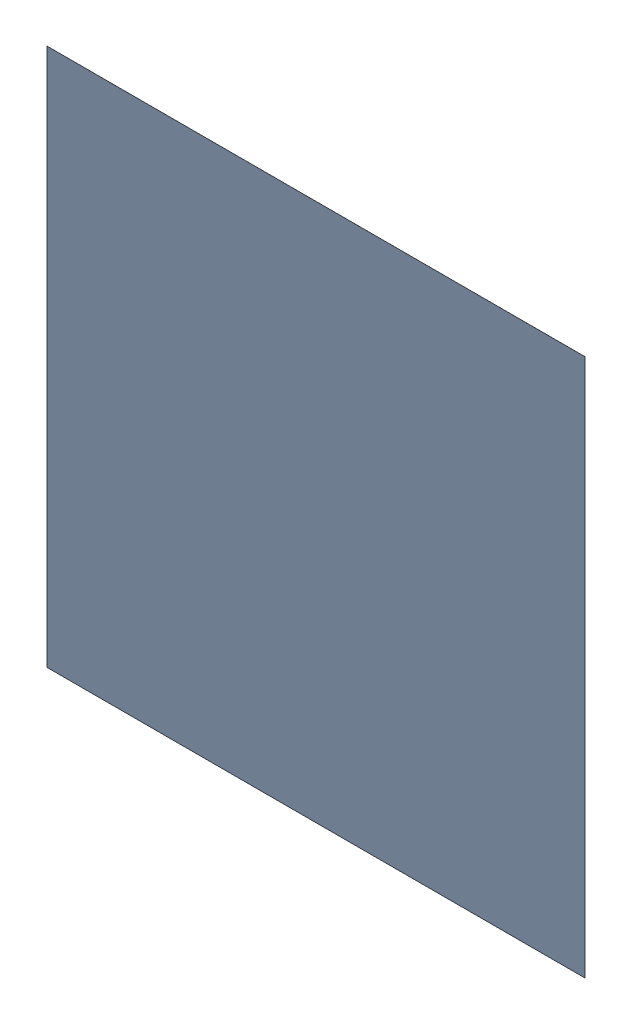
SolidWorks assembly X6, configuration Standard. Lengths in mm.
Overall size (0.05 0.05 0).
2 component instances, 1 part files, 0 mates.
Components (placement in the parent):
- 6269211456-1: 6269211456 [Standard] at (-2.6 -23.5 0) x (0 1 0) z (0 0 1) size (0.05 0.05 0)
  - Extruded-3-1: Extruded-3 [Standard] at origin size (0.05 0.05 0)
